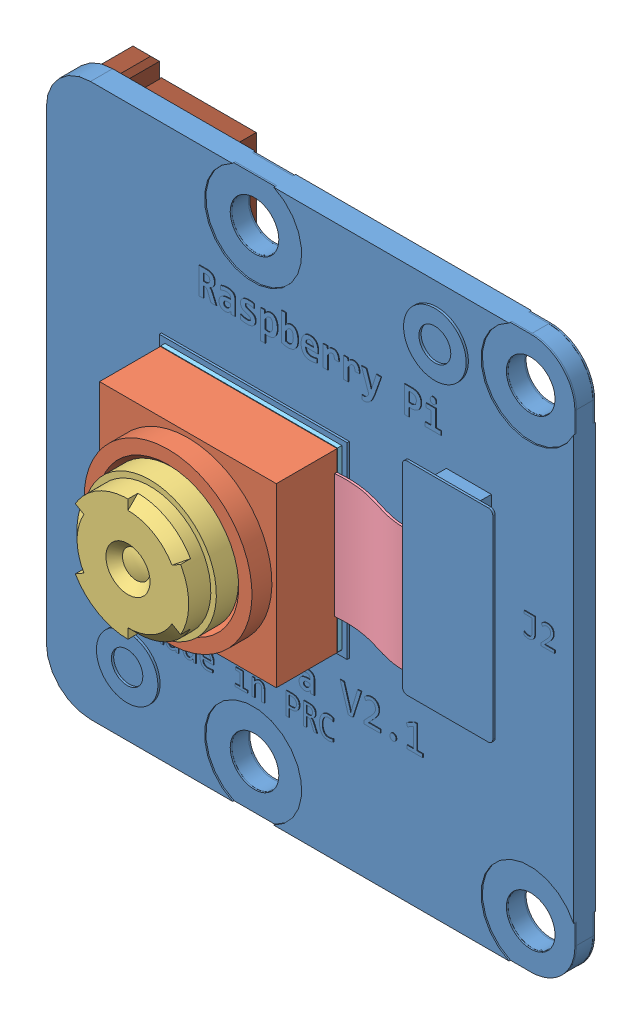
SolidWorks assembly RspCameraMia, configuration Default. Lengths in mm.
Overall size (23.86 25 9.96).
40 component instances, 22 part files, 0 mates.
Components (placement in the parent):
- PicameraPCB-1: PicameraPCB [Default] at (0.2393 -0.0199 0) x (-1 0 0) z (0 0 1) size (23.86 25 2.2)
- OVA5647_Housing-1: OVA5647_Housing [Default] at (-2.4078 0.0859 1) x (1 0 0) z (0 -1 0) size (8 3.95 8)
- OVA5647_Lens_FOV-1: OVA5647_Lens_FOV [Default] at (-2.4087 0.0921 5.963) x (1 0 0) z (0 -1 0) size (6 3.35 6)
- ribbon_cam-1: ribbon_cam [Default] at (-2.4804 0.3633 1.4162) x (0 1 0) z (1 0 0) size (5.6 1.19 4.76)
- CCD-1: CCD [Default] at (-2.0757 0.287 1.296) x (1 0 0) z (0 -1 0) size (8 0.68 8)
- CAPC-0805-T0.75-BN-1: CAPC-0805-T0.75-BN [Default] at (4.562 5.9833 -0.0026) x (0 -1 0) z (0 0 -1) size (2.1 1.35 0.75)
- CAPC-0805-T0.75-BN-2: CAPC-0805-T0.75-BN [Default] at (2.0233 10.2705 -0.0026) x (0 -1 0) z (0 0 -1) size (2.1 1.35 0.75)
- CAPC-0402-T0.55-BN-1: CAPC-0402-T0.55-BN [Default] at (-2.9562 6.224 -0.2572) x (-1 0 0) z (0 -1 0) size (1.05 0.55 0.55)
- CAPC-0402-T0.55-BN-2: CAPC-0402-T0.55-BN [Default] at (-2.9504 5.2898 -0.2691) x (-1 0 0) z (0 -1 0) size (1.05 0.55 0.55)
- CAPC-0402-T0.55-BN-3: CAPC-0402-T0.55-BN [Default] at (4.5768 -5.1833 -0.2811) x (-1 0 0) z (0 -1 0) size (1.05 0.55 0.55)
- CAPC-0402-T0.55-BN-4: CAPC-0402-T0.55-BN [Default] at (2.5547 -5.1368 -0.2811) x (-1 0 0) z (0 -1 0) size (1.05 0.55 0.55)
- CAPC-0402-T0.55-BN-5: CAPC-0402-T0.55-BN [Default] at (2.6129 -9.93 -0.293) x (-1 0 0) z (0 -1 0) size (1.05 0.55 0.55)
- CAPC-0402-T0.55-BN-6: CAPC-0402-T0.55-BN [Default] at (4.7286 -9.9294 -0.293) x (-1 0 0) z (0 -1 0) size (1.05 0.55 0.55)
- CAPC-0402-T0.55-BN-7: CAPC-0402-T0.55-BN [Default] at (8.4068 -3.8793 -0.2811) x (-1 0 0) z (0 -1 0) size (1.05 0.55 0.55)
- CAPC-0402-T0.55-BN-8: CAPC-0402-T0.55-BN [Default] at (9.0088 0.0217 -0.2796) x (0 1 0) z (-1 0 0) size (1.05 0.55 0.55)
- CAPC-0402-T0.55-BN-9: CAPC-0402-T0.55-BN [Default] at (10.4284 2.6731 -0.3022) x (0 1 0) z (-1 0 0) size (1.05 0.55 0.55)
- CAPC-0402-T0.55-BN-10: CAPC-0402-T0.55-BN [Default] at (8.2321 1.3259 -0.2838) x (1 0 0) z (0 1 0) size (1.05 0.55 0.55)
- RESC-0402-1: RESC-0402 [Default] at (3.7919 0.0148 -0.0114) x (1 0 0) z (0 0 -1) size (1.05 0.55 0.4)
- RESC-0402-2: RESC-0402 [Default] at (4.1232 2.6296 -0.0028) x (0 -1 0) z (0 0 -1) size (1.05 0.55 0.4)
- RESC-0402-3: RESC-0402 [Default] at (10.5883 -6.2795 -0.0019) x (0 1 0) z (0 0 -1) size (1.05 0.55 0.4)
- RESC-0603-1: RESC-0603 [Default] at (-2.6191 7.0617 -0.0121) x (1 0 0) z (0 0 -1) size (1.7 0.9 0.55)
- RESC-0603-2: RESC-0603 [Default] at (-3.4466 3.0018 -0.0048) x (0 -1 0) z (0 0 -1) size (1.7 0.9 0.55)
- RESC-1210-1: RESC-1210 [Default] at (2.2265 5.9002 -0.0068) x (0 -1 0) z (0 0 -1) size (3.3 2.7 0.6)
- c-1-1734248-5-e-raspberry_display-1: c-1-1734248-5-e-raspberry_display [Default] at (-10.6651 0.0449 -1.5) x (0 -1 0) z (-1 0 0) size (22.4 3.22 5.68)
- SOT23-5-1: SOT23-5 [Default] at (4.2989 9.8879 0.5457) x (0 -1 0) z (0 0 -1) size (2.91 3.01 1.23)
- SOT23-5-2: SOT23-5 [Default] at (3.5194 -3.2493 0.04) x (-1 0 0) z (0 0 -1) size (2.91 3.01 1.23)
- SOT23-5-3: SOT23-5 [Default] at (3.5816 -8.055 0.0206) x (-1 0 0) z (0 0 -1) size (2.91 3.01 1.23)
- KX7 SMD Quartz Crystal Resonator 3.2x2.5mm-1: KX7 SMD Quartz Crystal Resonator 3.2x2.5mm [Default] at (9.9746 -4.9221 0.0339) x (-1 0 0) z (0 -1 0) size (3.2 0.6 2.5)
- 70521906-1: 70521906 [Default] at (1.7167 0.8597 0.0159) size (2 2.1 0.95)
  - 70521906_01-1: 70521906_01 [Default] at origin size (0.25 0.55 0.75)
  - 70521906_02-1: 70521906_02 [Default] at origin size (0.25 0.55 0.75)
  - 70521906_03-1: 70521906_03 [Default] at origin size (2 1.25 0.9)
  - 70521906_04-1: 70521906_04 [Default] at origin size (0.25 0.55 0.75)
  - 70521906_05-1: 70521906_05 [Default] at origin size (0.25 0.55 0.75)
  - 70521906_06-1: 70521906_06 [Default] at origin size (0.25 0.55 0.75)
  - 70521906_07-1: 70521906_07 [Default] at origin size (0.25 0.55 0.75)
- c6aaa-1: c6aaa [Default] at (0.0643 0.0942 0) x (1 0 0) z (0 0 -1) size (2.01 2.99 0.61)
- 4pin_smd-1: 4pin_smd [Default] at (0.027 0.0676 0) x (1 0 0) z (0 0 -1) size (1.29 1 0.47)
- 4pin_smd-2: 4pin_smd [Default] at (-0.0093 -6.0092 -0.0198) x (1 0 0) z (0 0 -1) size (1.29 1 0.47)
- 4pin_smd-3: 4pin_smd [Default] at (0.0326 -3.0068 -0.0235) x (1 0 0) z (0 0 -1) size (1.29 1 0.47)
